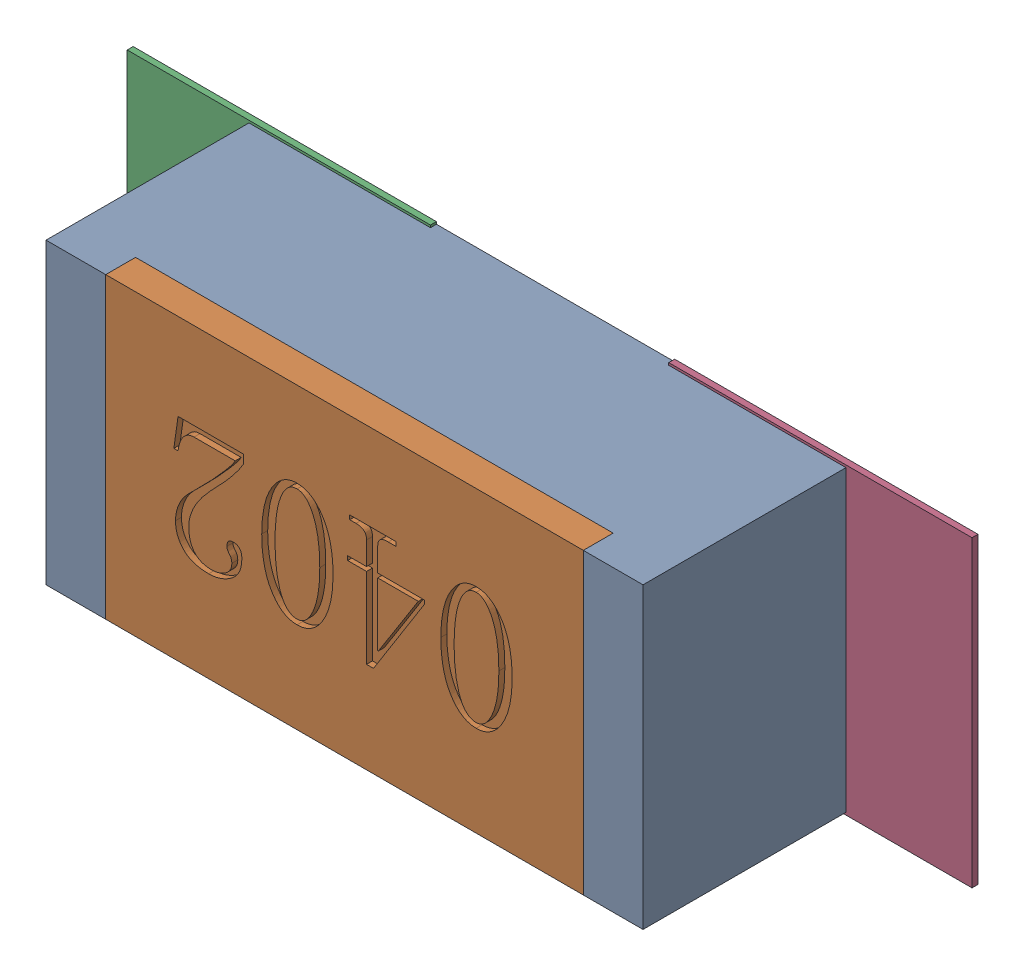
SolidWorks assembly R106, configuration Défaut. Lengths in mm.
Overall size (1.42 0.51 0.35).
5 component instances, 2 part files, 0 mates.
Components (placement in the parent):
- R0402-1: R0402 [Défaut] at (8.1534 -38.0237 0) x (-1 0 0) z (0 0 1) size (1 0.5 0.35)
- 6504207776-1: 6504207776 [Défaut] at (7.7034 -38.0238 0) size (0.51 0.51 0.01)
  - Extruded-1: Extruded [Défaut] at origin size (0.51 0.51 0.01)
- 6504207776-2: 6504207776 [Défaut] at (8.6105 -38.0238 0) size (0.51 0.51 0.01)
  - Extruded-1: Extruded [Défaut] at origin size (0.51 0.51 0.01)
